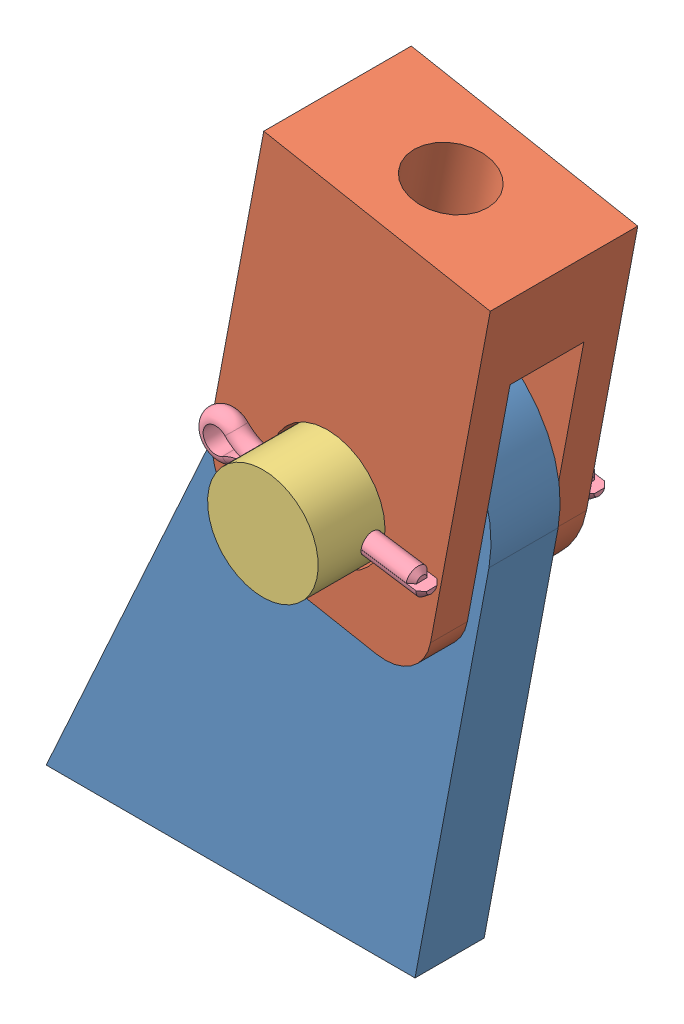
SolidWorks assembly Clevis Fixture Assembly, configuration Default. Lengths in mm.
Overall size (133.76 192.64 76.2).
5 component instances, 4 part files, 11 mates.
Components (placement in the parent):
- Plate-1: Plate [Default] at origin size (122.55 147.96 19.05)
- Tie Rod End-1: Tie Rod End [Default] at (-4.7055 -24.9603 10.16) x (0.185257 0.98269 0) z (0.98269 -0.185257 0) size (101.6 40.64 63.5)
- Pin-1: Pin [Default] at (0 0 10.16) x (0.98891 -0.148514 0) z (-0.148514 -0.98891 0) size (30.48 76.2 30.48)
- Cotter Pin-1: Cotter Pin [98355A300] at (28.6642 -4.2791 -13.0175) x (0.98891 -0.148514 0) z (0 0 1) size (63.61 12.7 5.71)
- Cotter Pin-2: Cotter Pin [98355A300] at (28.8289 -4.3552 33.337) x (0.98891 -0.148514 0) z (-0.00264 -0.017578 0.999842) size (63.61 12.7 5.71)
Mates (geometry in assembly coordinates):
- Coincident1: coincident: plane of Plate-1 through (0 0 0) normal (0 0 -1); plane of Tie Rod End-1 through (-36.363 -21.5028 0) normal (0 0 1)
- Coincident2: coincident: cylinder of Plate-1 through (0 0 19.05) axis (0 0 -1) radius 15.875; circle of Tie Rod End-1
- Concentric1: concentric: cylinder of Tie Rod End-1 through (0 0 -20.32) axis (0 0 1) radius 15.875; cylinder of Pin-1 through (0 0 48.26) axis (0 0 -1) radius 15.24
- Parallel1: parallel: plane of Plate-1 through (33.0724 -6.2348 19.05) normal (0.98269 -0.185257 0); plane of Tie Rod End-1 through (26.4949 -30.8422 10.16) normal (0.98269 -0.185257 0)
- Concentric2: concentric: cylinder of Pin-1 through (-15.071 2.2633 -13.0175) axis (0.98891 -0.148514 0) radius 2.921; cylinder of Cotter Pin-1 through (-15.2966 2.2972 -13.0175) axis (0.98891 -0.148514 0) radius 2.8575
- Tangent1: tangent: plane of Tie Rod End-1 through (-17.5409 78.3385 -10.16) normal (0 0 -1); cylinder of Cotter Pin-1 through (-15.2966 2.2972 -13.0175) axis (0.98891 -0.148514 0) radius 2.8575
- Coincident3: coincident: plane of Tie Rod End-1 through (-17.5409 78.3385 -10.16) normal (0 0 -1); line of Cotter Pin-1 through (-15.2966 2.2972 -10.16) axis (0.98891 -0.148514 0)
- Lock4: lock: unknown of Tie Rod End-1; unknown of Cotter Pin-1
- Concentric8: concentric: cylinder of Pin-1 through (-15.071 2.2633 33.3375) axis (0.98891 -0.148514 0) radius 2.921; cylinder of Cotter Pin-2 through (-15.1244 2.2714 33.3375) axis (0.98891 -0.148514 0) radius 2.8575
- Coincident7: coincident: plane of Tie Rod End-1 through (-36.363 -21.5028 30.48) normal (0 0 1); line of Cotter Pin-2 through (-15.1244 2.2714 30.4795) axis (0.98891 -0.148514 0)
- Lock6: lock: unknown of Tie Rod End-1; unknown of Cotter Pin-2
